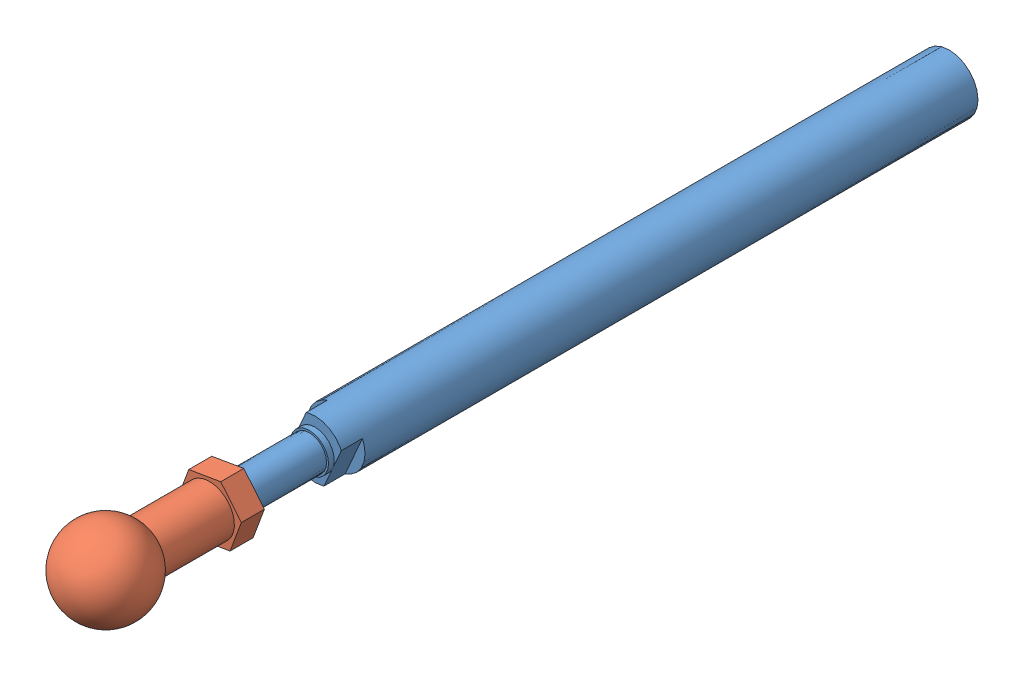
SolidWorks assembly Assemblage3, configuration Défaut. Lengths in mm.
Overall size (25.18 26.83 230.5).
2 component instances, 2 part files, 2 mates.
Components (placement in the parent):
- tige_verin-1: tige_verin [Défaut] at origin size (15 15 186.5)
- joint_rotule_femelle-1: joint_rotule_femelle [Défaut] at (0 0 271.5) x (-0.954092 -0.299513 0) z (0 0 -1) size (19.49 22 44)
Mates (geometry in assembly coordinates):
- Coïncidente1: coincident: plane of tige_verin-1 through (0 0 238.5) normal (0 0 1); plane of ? through (-100.3223 3.3194 238.5) normal (0 0 -1)
- Coaxiale1: concentric aligned: cylinder of tige_verin-1; cylinder of ?
